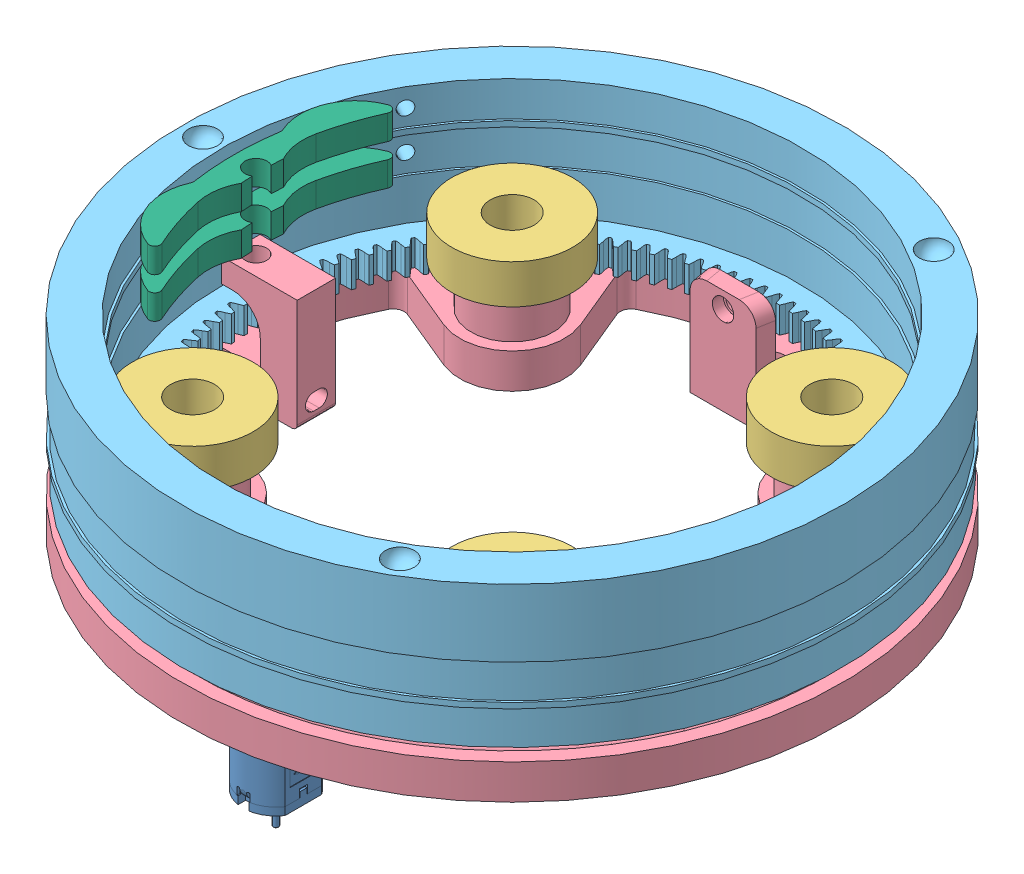
SolidWorks assembly motor_assembly, configuration Default. Lengths in mm.
Overall size (163.85 59.2 163.85).
12 component instances, 7 part files, 26 mates.
Components (placement in the parent):
- pololu_micro_motor-1: pololu_micro_motor [Default] at (-0.2 -3.65 42.8) x (0 0 1) z (0 1 0) size (12.01 10.08 40.2)
- big_gear-1: big_gear [Default] at (0 9.85 40) x (0 1 0) z (0.999817 0 -0.019111) size (3 17.6 17.6)
- bearing_8mm-1: bearing_8mm [Default] at (-29.0833 14.35 -29.0833) x (0.025444 0 0.999676) z (-0.999676 0 0.025444) size (22 7.12 22)
- bearing_8mm-2: bearing_8mm [Default] at (29.0833 14.35 29.0833) x (0.782279 0 0.622928) z (-0.622928 0 0.782279) size (22 7.12 22)
- new_new_plate-1: new_new_plate [Default] x (0 1 0) z (1 0 0) size (20.65 120 120)
- bearing_8mm-3: bearing_8mm [Default] at (-29.0833 14.35 29.0833) x (-0.159057 0 0.987269) z (-0.987269 0 -0.159057) size (22 7.12 22)
- bearing_8mm-4: bearing_8mm [Default] at (29.0833 14.35 -29.0833) x (-0.999918 0 0.012803) z (-0.012803 0 -0.999918) size (22 7.12 22)
- outer_rotator-3: outer_rotator [Default] at (0 12.35 0) x (0 1 0) z (0.866815 0 0.498631) size (26 120 120)
- inner_brush-1: inner_brush [Default] at (-46.63 29.85 0) x (0 0 -1) z (0 1 0) size (43.9 7.9 4.5)
- inner_brush-2: inner_brush [Default] at (-46.63 22.5 0) x (0 0 -1) z (0 1 0) size (43.9 7.9 4.5)
- outer_brush-1: outer_brush [Default] at (-46.4993 20.216 -46.4993) x (-0.707107 0 0.707107) z (0 -1 0) size (50.59 10.28 4.5)
- outer_brush-2: outer_brush [Default] at (-46.4993 10.2 -46.4993) x (0.707107 0 -0.707107) z (0 1 0) size (50.59 10.28 4.5)
Mates (geometry in assembly coordinates):
- Concentric18: concentric aligned: cylinder of big_gear-1 through (0 11.35 40) axis (0 -1 0) radius 1.5; cylinder of new_new_plate-1 through (0 41.6181 40) axis (0 -1 0) radius 2.5
- Concentric19: concentric anti-aligned: cylinder of bearing_8mm-2 through (29.0833 21.47 29.0833) axis (0 -1 0) radius 4; cylinder of new_new_plate-1 through (29.0833 0 29.0833) axis (0 1 0) radius 3.9
- Coincident35: coincident anti-aligned: plane of bearing_8mm-2 through (29.0833 14.35 29.0833) normal (0 -1 0); plane of new_new_plate-1 through (29.0833 14.35 29.0833) normal (0 1 0)
- Coincident37: coincident anti-aligned: plane of new_new_plate-1 through (-29.0833 14.35 29.0833) normal (0 1 0); plane of bearing_8mm-3 through (-29.0833 14.35 29.0833) normal (0 -1 0)
- Coincident39: coincident anti-aligned: plane of pololu_micro_motor-1 through (4.8 5.35 36.8) normal (0 1 0); plane of new_new_plate-1 through (0 5.35 0) normal (0 -1 0)
- Coincident40: coincident anti-aligned: plane of pololu_micro_motor-1 through (-5.2 5.35 48.8) normal (-1 0 0); plane of new_new_plate-1 through (-5.2 24.6027 33.8) normal (1 0 0)
- Coincident41: coincident anti-aligned: plane of pololu_micro_motor-1 through (4.8 5.35 48.8) normal (0 0 1); plane of new_new_plate-1 through (5.2 24.6027 48.8) normal (0 0 -1)
- Coincident42: coincident anti-aligned: plane of new_new_plate-1 through (0 0 0) normal (0 -1 0); plane of assembly through (0 0 0) normal (0 1 0)
- Coincident44: coincident aligned: plane of new_new_plate-1; plane of assembly through (0 0 0) normal (0 0 1)
- Coincident45: coincident aligned: plane of new_new_plate-1 through (0 0 0) normal (1 0 0); plane of assembly through (0 0 0) normal (1 0 0)
- Distance1: distance = 2 mm anti-aligned: plane of outer_rotator-3 through (0 8.35 0) normal (0 -1 0); plane of new_new_plate-1 through (0 6.35 0) normal (0 1 0)
- Concentric23: concentric anti-aligned: cylinder of new_new_plate-1 through (0 6.35 0) axis (0 -1 0) radius 60; cylinder of outer_rotator-3 through (0 8.35 0) axis (0 1 0) radius 60
- Coincident46: coincident aligned: plane of big_gear-1 through (0.1682 8.35 48.7984) normal (0 -1 0); plane of outer_rotator-3 through (0 8.35 0) normal (0 -1 0)
- Concentric24: concentric anti-aligned: cylinder of new_new_plate-1 through (-29.0833 0 29.0833) axis (0 1 0) radius 3.9; cylinder of bearing_8mm-3 through (-29.0833 21.47 29.0833) axis (0 -1 0) radius 4
- Concentric25: concentric anti-aligned: cylinder of bearing_8mm-1 through (-29.0833 21.47 -29.0833) axis (0 -1 0) radius 4; cylinder of new_new_plate-1 through (-29.0833 0 -29.0833) axis (0 1 0) radius 3.9
- Coincident47: coincident anti-aligned: plane of bearing_8mm-1 through (-29.0833 14.35 -29.0833) normal (0 -1 0); plane of new_new_plate-1 through (-29.0833 14.35 -29.0833) normal (0 1 0)
- Concentric26: concentric anti-aligned: circle of new_new_plate-1; cylinder of bearing_8mm-4 through (29.0833 21.47 -29.0833) axis (0 -1 0) radius 4
- Coincident49: coincident anti-aligned: plane of new_new_plate-1 through (29.0833 14.35 -29.0833) normal (0 1 0); plane of bearing_8mm-4 through (29.0833 14.35 -29.0833) normal (0 -1 0)
- Concentric27: concentric anti-aligned: cylinder of new_new_plate-1 through (-46.4993 -5.3033 -46.4993) axis (0 1 0) radius 1.875; cylinder of outer_brush-2 through (-46.4993 14.7 -46.4993) axis (0 -1 0) radius 2
- Coincident50: coincident anti-aligned: plane of outer_rotator-3 through (-29.9178 14.7 52.0089) normal (0 -1 0); plane of outer_brush-2 through (-24.8777 14.7 -24.8777) normal (0 1 0)
- Concentric28: concentric anti-aligned: cylinder of outer_brush-1 through (-46.4993 15.716 -46.4993) axis (0 1 0) radius 2; cylinder of outer_brush-2 through (-46.4993 14.7 -46.4993) axis (0 -1 0) radius 2
- Coincident51: coincident anti-aligned: plane of outer_rotator-3 through (-29.9178 15.716 52.0089) normal (0 1 0); plane of outer_brush-1 through (-24.8777 15.716 -24.8777) normal (0 -1 0)
- Concentric29: concentric anti-aligned: cylinder of new_new_plate-1 through (-46.63 10.8346 0) axis (0 1 0) radius 1.95; cylinder of inner_brush-2 through (-46.63 27 0) axis (0 -1 0) radius 2
- Concentric30: concentric anti-aligned: cylinder of new_new_plate-1 through (-46.63 10.8346 0) axis (0 1 0) radius 1.95; cylinder of inner_brush-1 through (-46.63 34.35 0) axis (0 -1 0) radius 2
- Coincident52: coincident anti-aligned: plane of outer_rotator-3 through (-26.1183 27 45.4037) normal (0 -1 0); plane of inner_brush-2 through (-22.2075 27 0) normal (0 1 0)
- Coincident53: coincident aligned: plane of outer_rotator-3 through (0 34.35 0) normal (0 1 0); plane of inner_brush-1 through (-22.2075 34.35 0) normal (0 1 0)
